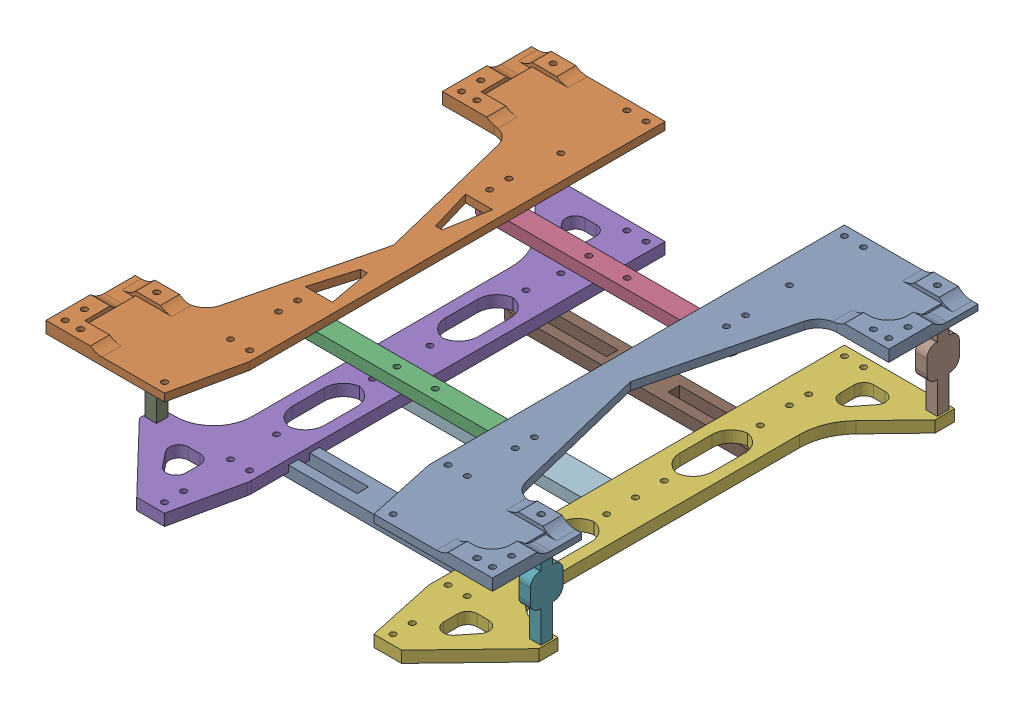
SolidWorks assembly ChassiAsm, configuration Default. Lengths in mm.
Overall size (232.61 68.2 256.52).
13 component instances, 7 part files, 13 mates.
Components (placement in the parent):
- TopLegConnector-1: TopLegConnector [Default] at (83.1462 15.8967 145.4241) x (-0.000184 0 -1) z (1 0 -0.000184) size (253 6 69.6)
- TopLegConnectorOTHASIDE-1: TopLegConnectorOTHASIDE [Default] at (-139.4167 17.8967 145.4416) x (-0.000167 0 -1) z (-1 0 0.000167) size (253 6 69.6)
- BonesTop-1: BonesTop [Default] at (-89.827 8.8967 73.9333) size (133.82 6 19.11)
- BonesTop-2: BonesTop [Default] at (33.5146 8.8967 -26.0667) x (-1 0 0) z (0 0 -1) size (133.82 6 19.11)
- BottomLegConnector-1: BottomLegConnector [Default] at (-139.4573 -38.3033 145.4397) x (0 0 -1) z (-1 0 0) size (253 6 57.37)
- BottomLegConnector-2: BottomLegConnector [Default] at (83.1015 -38.3033 145.4262) x (0 0 -1) z (1 0 0) size (253 6 57.37)
- Balero6mmHolder-1: Balero6mmHolder [Default] at (74.9595 -10.2033 108.9262) x (0 0 1) z (0 -1 0) size (17 6 50.2)
- Balero6mmHolder-2: Balero6mmHolder [Default] at (74.9215 -10.2033 -97.5738) x (0 0 1) z (0 -1 0) size (17 6 50.2)
- Balero6mmHolder-3: Balero6mmHolder [Default] at (-131.2773 -10.2033 108.9397) x (0 0 -1) z (0 -1 0) size (17 6 50.2)
- Balero6mmHolder-4: Balero6mmHolder [Default] at (-131.2773 -10.2033 -97.5603) x (0 0 -1) z (0 -1 0) size (17 6 50.2)
- Bones-1: Bones [Default] at (-89.1988 -47.3033 -44.3826) size (138 6 16)
- BonesMiddleBottom-1: BonesMiddleBottom [Default] at (-89.157 -47.3033 20.6039) size (138 6 38)
- Bones-2: Bones [Default] at (-89.1988 -44.0518 85.6174) size (138 6 16)
Mates (geometry in assembly coordinates):
- Coincident1: coincident anti-aligned: circle of TopLegConnectorOTHASIDE-1; circle of BonesTop-1
- Coincident2: coincident anti-aligned: circle of TopLegConnectorOTHASIDE-1; circle of BonesTop-2
- Coincident3: coincident aligned: circle of TopLegConnector-1; circle of BonesTop-2
- Coincident4: coincident aligned: circle of TopLegConnector-1; circle of BonesTop-1
- Coincident6: coincident anti-aligned: circle of BottomLegConnector-2; circle of Balero6mmHolder-2
- Coincident8: coincident aligned: circle of TopLegConnector-1; circle of Balero6mmHolder-2
- Coincident9: coincident anti-aligned: circle of TopLegConnector-1; circle of Balero6mmHolder-1
- Coincident10: coincident anti-aligned: circle of TopLegConnectorOTHASIDE-1; circle of Balero6mmHolder-4
- Coincident11: coincident aligned: circle of BottomLegConnector-1; circle of Balero6mmHolder-4
- Coincident13: coincident anti-aligned: circle of BottomLegConnector-1; circle of Balero6mmHolder-3
- Coincident14: coincident aligned: circle of BottomLegConnector-2; circle of BonesMiddleBottom-1
- Concentric1: concentric aligned: cylinder of BottomLegConnector-1 through (-89.1988 -35.3033 -44.3826) axis (0 -1 0) radius 1.5; cylinder of Bones-1 through (-89.1988 -41.3033 -44.3826) axis (0 -1 0) radius 1.5
- Concentric2: concentric aligned: cylinder of BottomLegConnector-1 through (-89.1988 -35.3033 85.6174) axis (0 -1 0) radius 1.5; cylinder of Bones-2 through (-89.1988 -38.0518 85.6174) axis (0 -1 0) radius 1.5
